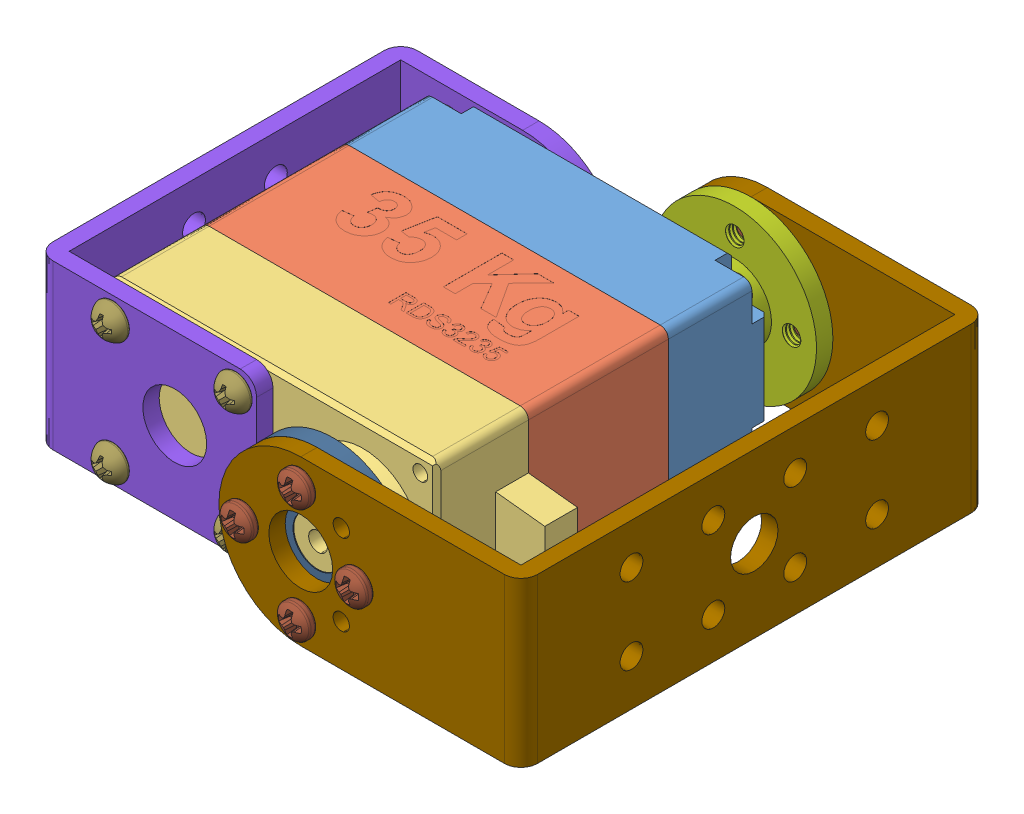
SolidWorks assembly RDS3235, configuration По умолчанию. Lengths in mm.
Overall size (64.79 20 60.22).
32 component instances, 13 part files, 0 mates.
Components (placement in the parent):
- RDS3235_1.step-1: RDS3235_1.step [По умолчанию] at origin size (46 20 51.81)
  - Component10.step-1: Component10.step [По умолчанию] at (-32.9692 11.2797 69.5938) size (40 20 13.7)
  - Component11.step-1: Component11.step [По умолчанию] at (-32.9692 11.2797 69.5938) size (40 20 17.1)
  - Component12.step-1: Component12.step [По умолчанию] at (-32.9692 11.2797 69.5938) size (46 20 16.7)
  - Screw 3.step-1: Screw 3.step [По умолчанию] at (-15.2192 29.0297 54.3438) x (-1 0 0) z (0 0 -1) size (3.2 3.2 4.35)
  - Screw 3.step-2: Screw 3.step [По умолчанию] at (-50.7192 29.0297 54.3438) x (-1 0 0) z (0 0 -1) size (3.2 3.2 4.35)
  - Screw 3.step-3: Screw 3.step [По умолчанию] at (-15.2192 13.5297 54.3438) x (-1 0 0) z (0 0 -1) size (3.2 3.2 4.35)
  - Screw 3.step-4: Screw 3.step [По умолчанию] at (-50.9133 13.4084 54.3438) x (-1 0 0) z (0 0 -1) size (3.2 3.2 4.35)
  - RDS3235_Gear 25R 0.00.step-1: RDS3235_Gear 25R 0.00.step [По умолчанию] at (-21.9777 21.2797 43.5438) size (6.47 6.49 4.31)
- Wheel_gear.step-1: Wheel_gear.step [По умолчанию] at (-21.9777 21.2797 42.4438) x (1 0 0) z (0 -1 0) size (20 4.65 20)
  - Healical Gear (25R@0.00).step-1: Healical Gear (25R@0.00).step [По умолчанию] at (0 1.1 0) x (1 0 0) z (0 1 0) size (6.47 6.49 3.51)
  - Wheel_gear-0.step-1: Wheel_gear-0.step [По умолчанию] at origin size (20 4.14 20)
- Support_small.step-1: Support_small.step [По умолчанию] at (-46.4192 11.2797 69.5938) x (0 0 1) z (-1 0 0) size (44.5 20 26.9)
- Support_large.step-1: Support_large.step [По умолчанию] at (-13.5277 11.2797 68.9438) x (0 0 -1) z (1 0 0) size (57 20 36.9)
- Wheel.step-1: Wheel.step [По умолчанию] at (-21.9777 21.2797 95.4438) x (1 0 0) z (0 1 0) size (20 2.94 20)
- Screw 2.step-1: Screw 2.step [По умолчанию] at (-21.9777 28.2797 43.4438) x (-1 0 0) z (0 0 -1) size (4 4 4.61)
- Screw 2.step-2: Screw 2.step [По умолчанию] at (-28.9777 21.2797 43.4438) x (0 -1 0) z (0 0 -1) size (4 4 4.61)
- Screw 2.step-3: Screw 2.step [По умолчанию] at (-21.9777 14.2797 43.4438) x (1 0 0) z (0 0 -1) size (4 4 4.61)
- Screw 2.step-4: Screw 2.step [По умолчанию] at (-14.9777 21.2797 43.4438) x (0 1 0) z (0 0 -1) size (4 4 4.61)
- Screw 1.step-1: Screw 1.step [По умолчанию] at (-42.9692 28.2797 47.3438) x (-1 0 0) z (0 0 -1) size (4.2 4.2 8.22)
- Screw 1.step-2: Screw 1.step [По умолчанию] at (-49.9692 21.2797 47.3438) x (0 -1 0) z (0 0 -1) size (4.2 4.2 8.22)
- Screw 1.step-3: Screw 1.step [По умолчанию] at (-42.9692 14.2797 47.3438) x (1 0 0) z (0 0 -1) size (4.2 4.2 8.22)
- Screw 1.step-4: Screw 1.step [По умолчанию] at (-35.9692 21.2797 47.3438) x (0 1 0) z (0 0 -1) size (4.2 4.2 8.22)
- Screw 2.step-5: Screw 2.step [По умолчанию] at (-21.9777 28.2797 94.4438) x (-1 0 0) z (0 0 1) size (4 4 4.61)
- Screw 2.step-6: Screw 2.step [По умолчанию] at (-14.9777 21.2797 94.4438) x (0 1 0) z (0 0 1) size (4 4 4.61)
- Screw 2.step-7: Screw 2.step [По умолчанию] at (-21.9777 14.2797 94.4438) size (4 4 4.61)
- Screw 2.step-8: Screw 2.step [По умолчанию] at (-28.9777 21.2797 94.4438) x (0 -1 0) z (0 0 1) size (4 4 4.61)
- Screw 1.step-5: Screw 1.step [По умолчанию] at (-50.4692 28.7797 91.8438) x (-1 0 0) z (0 0 1) size (4.2 4.2 8.22)
- Screw 1.step-6: Screw 1.step [По умолчанию] at (-35.4692 28.7797 91.8438) x (0 1 0) z (0 0 1) size (4.2 4.2 8.22)
- Screw 1.step-7: Screw 1.step [По умолчанию] at (-35.4692 13.7797 91.8438) size (4.2 4.2 8.22)
- Screw 1.step-8: Screw 1.step [По умолчанию] at (-50.4692 13.7797 91.8438) x (0 -1 0) z (0 0 1) size (4.2 4.2 8.22)
- Screw 4.step-1: Screw 4.step [По умолчанию] at (-21.9777 21.2797 42.4438) x (1 0 0) z (0 0 -1) size (5.6 5.6 8.59)
